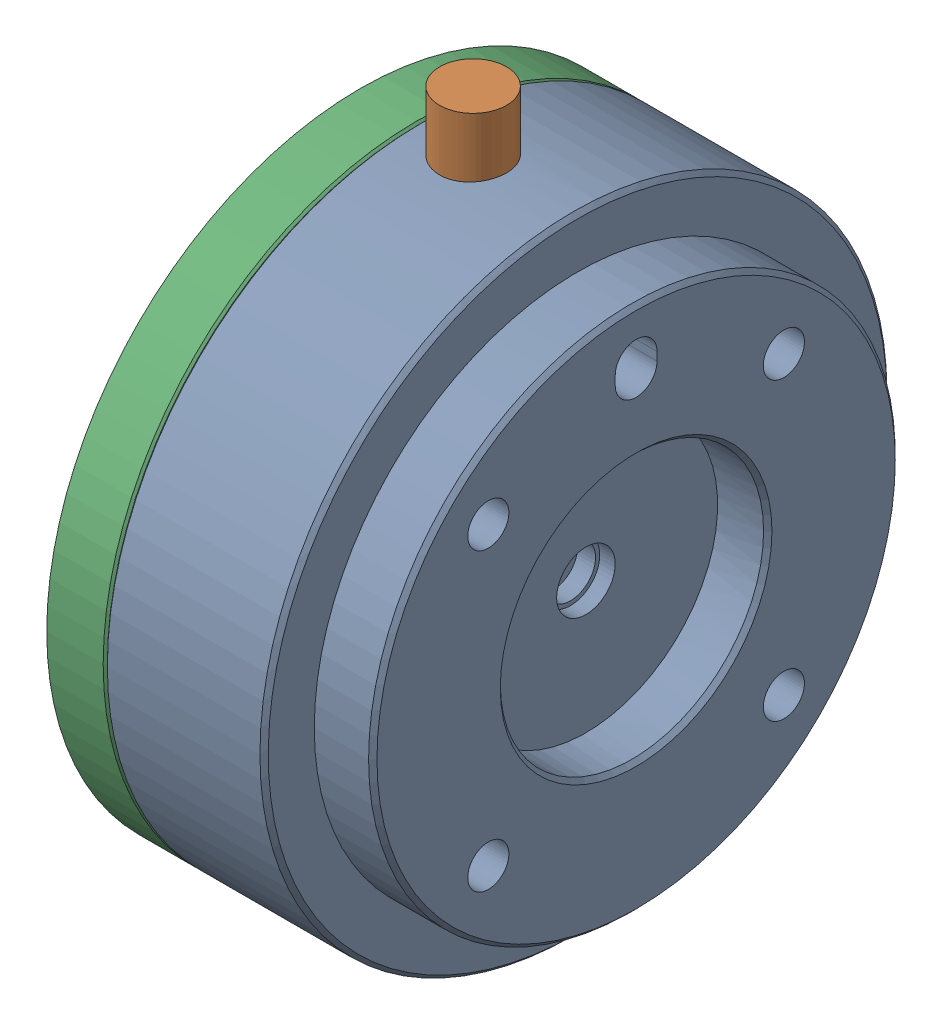
SolidWorks assembly 1-Simple_Size 1_Tool flange_r00, configuration 默认. Lengths in mm.
Overall size (33 82 75).
2 component instances, 2 part files, 0 mates.
Components (placement in the parent):
- 1-Size 1_Tool flange_r03AA_Simple-1: 1-Size 1_Tool flange_r03AA_Simple [默认] at (-0.5 0 0) size (26 82 75)
- 1-Size 1_Tool flange temporary extension_r03AA_Simple-1: 1-Size 1_Tool flange temporary extension_r03AA_Simple [默认] at origin size (14 75 75)
